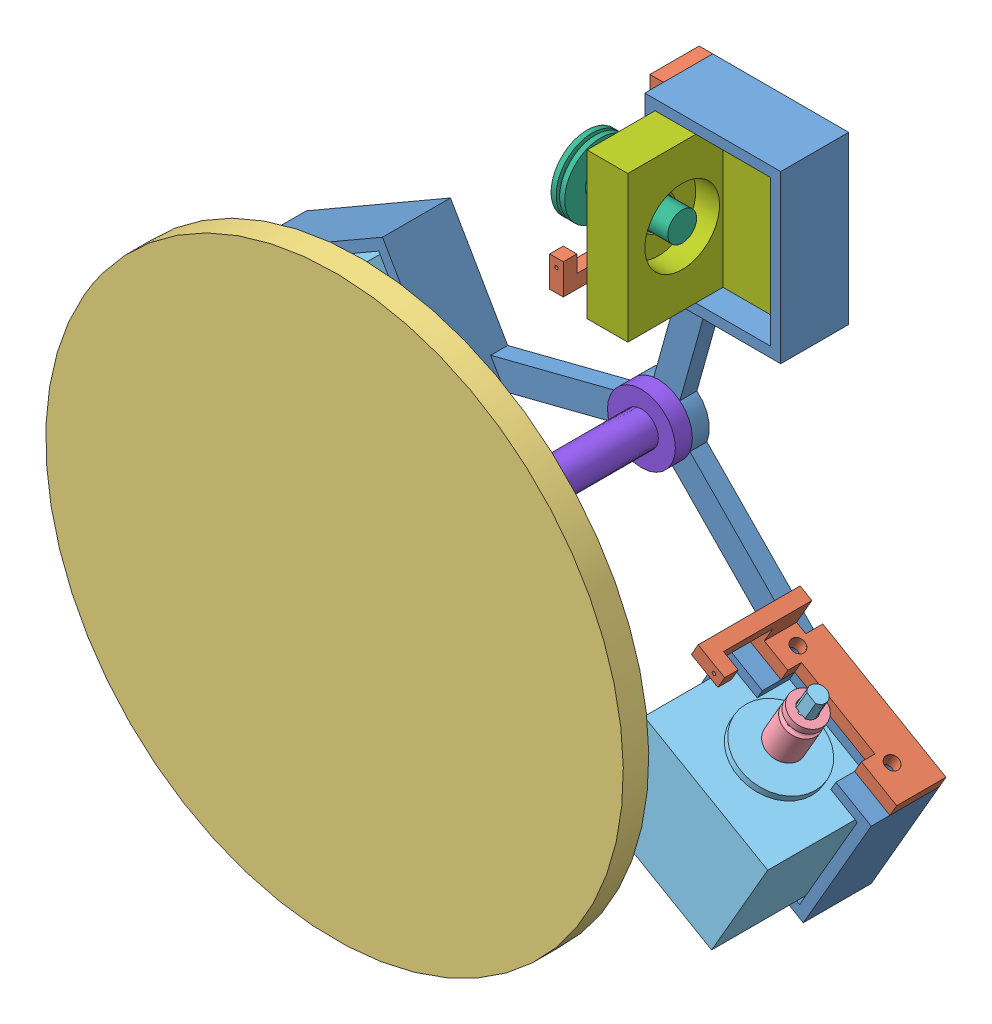
SolidWorks assembly angling2, configuration Default. Lengths in mm.
Overall size (235.3 235.3 100.33).
12 component instances, 8 part files, 31 mates.
Components (placement in the parent):
- Base-1: Base [Default] x (1 0 0) z (0 -1 0) size (186.28 20 188.17)
- cable guide-1: cable guide [Default] at (11 0 0) x (0 -1 0) z (-1 0 0) size (49 35 13)
- panel-1: panel [Default] at (0 0 92.825) x (-0.837169 0.546944 0) z (0 0 1) size (170 170 8.5)
- cable pulley-1: cable pulley [Default] at (-61.8538 -36.866 24) x (-0.866025 -0.5 0) z (-0.5 0.866025 0) size (10 10 14)
- Stepper motor-1: Stepper motor [Default] at (-69.3538 -23.8756 24) x (-0.866025 -0.5 0) z (-0.5 0.866025 0) size (42 42 57)
- Spring pulley-1: Spring pulley [Default] at (26 92.5 -47.5) x (0 -1 0) z (-1 0 0) size (21.17 21.17 28)
- Spring holde-1: Spring holde [Default] at (14 93 3) x (0 -1 0) z (-1 0 0) size (43 37 34)
- Stepper motor-2: Stepper motor [Default] at (53.9878 -48.4904 24) x (0.866025 -0.5 0) z (-0.5 -0.866025 0) size (42 42 57)
- cable pulley-2: cable pulley [Default] at (61.4878 -35.5 24) x (0.866025 -0.5 0) z (-0.5 -0.866025 0) size (10 10 14)
- cable guide-2: cable guide [Default] at (-5.5 -9.5263 0) x (-0.866025 0.5 0) z (0.5 0.866025 0) size (49 35 13)
- cable guide-3: cable guide [Default] at (-5.5 9.5263 0) x (0.866025 0.5 0) z (0.5 -0.866025 0) size (49 35 13)
- Pillar-4: Pillar [Default] x (1 0 0) z (0 -1 0) size (20 97.83 20)
Mates (geometry in assembly coordinates):
- InPlace1: in place: plane of assembly through (11 10.5 -96) normal (-1 0 0); plane of ? through (11 0 0) normal (-1 0 0); moOrthogonalPlaneRef_w of assembly through (11 10.5 -96) normal (-1 0 0); plane of ? through (11 0 0) normal (0 1 0); plane of assembly through (11 10.5 -96) normal (-1 0 0); plane of ? through (11 0 0) normal (0 0 1); plane of ? through (11 96 10.5) normal (-1 0 0); unknown of cable guide-1
- Coincident1: coincident aligned: plane of ?; plane of ?
- Coincident2: coincident aligned: moOrthogonalPlaneRef_w of Base-1; plane of Part3^angling2-1 through (11 0 0) normal (0 0 1)
- Coincident3: coincident anti-aligned: moOrthogonalPlaneRef_w of Base-1; plane of Part3^angling2-1 through (11 0 0) normal (0 -1 0)
- Coincident15: coincident anti-aligned: plane of Base-1 through (14 93 10.5) normal (1 0 0); plane of Part7^angling2-1 through (14 93 3) normal (-1 0 0)
- Coincident17: coincident anti-aligned: plane of Base-1 through (0 0 3) normal (0 0 1); plane of Part7^angling2-1 through (26 93 3) normal (0 0 -1)
- Coincident18: coincident anti-aligned: plane of Base-1 through (48 93 10.5) normal (0 -1 0); plane of Part7^angling2-1 through (26 93 3) normal (0 1 0)
- Coincident19: coincident aligned: plane of Part9^angling2-1 through (19 71.5 24) normal (1 0 0); plane of Part7^angling2-1 through (19 71.5 24) normal (1 0 0)
- Coincident20: coincident anti-aligned: plane of Base-1 through (-104.5404 -4.9308 10.5) normal (0.866025 0.5 0); plane of Part6^angling2-1 through (-104.0404 -5.7968 3) normal (-0.866025 -0.5 0)
- Coincident21: coincident anti-aligned: plane of Base-1 through (0 0 3) normal (0 0 1); plane of Part6^angling2-1 through (-67.6673 15.2032 3) normal (0 0 -1)
- Coincident22: coincident anti-aligned: plane of Base-1 through (-87.5404 -34.3756 10.5) normal (-0.5 0.866025 0); plane of Part6^angling2-1 through (-69.3538 -23.8756 24) normal (0.5 -0.866025 0)
- Coincident24: coincident anti-aligned: plane of cable pulley-1 through (-67.3538 -27.3397 24) normal (-0.5 0.866025 0); plane of Part6^angling2-1 through (-67.3538 -27.3397 24) normal (0.5 -0.866025 0)
- Concentric4: concentric aligned: cylinder of cable pulley-1 through (-60.3538 -39.4641 24) axis (-0.5 0.866025 0) radius 2.7; cylinder of Part6^angling2-1 through (-57.3538 -44.6603 24) axis (-0.5 0.866025 0) radius 2.5
- Parallel1: parallel anti-aligned: plane of cable pulley-1 through (-61.7094 -40.2467 26.2) normal (0 0 -1); plane of Part6^angling2-1 through (-67.3538 -27.3397 26) normal (0 0 1)
- Parallel2: parallel anti-aligned: plane of Part6^angling2-2 through (55.9878 -45.0263 26) normal (0 0 1); plane of cable pulley-2 through (64.3433 -33.6845 26.2) normal (0 0 -1)
- Concentric5: concentric aligned: cylinder of Part6^angling2-2 through (65.9878 -27.7058 24) axis (-0.5 -0.866025 0) radius 2.5; cylinder of cable pulley-2 through (62.9878 -32.9019 24) axis (-0.5 -0.866025 0) radius 2.7
- Coincident26: coincident anti-aligned: plane of Part6^angling2-2 through (55.9878 -45.0263 24) normal (0.5 0.866025 0); plane of cable pulley-2 through (55.9878 -45.0263 24) normal (-0.5 -0.866025 0)
- Coincident27: coincident anti-aligned: plane of Base-1 through (19.3013 -66.5692 10.5) normal (0.5 0.866025 0); plane of Part6^angling2-2 through (37.4878 -77.0692 24) normal (-0.5 -0.866025 0)
- Coincident28: coincident anti-aligned: plane of Base-1 through (36.3013 -37.1244 10.5) normal (0.866025 -0.5 0); plane of Part6^angling2-2 through (19.3013 -66.5692 3) normal (-0.866025 0.5 0)
- Coincident29: coincident anti-aligned: plane of Base-1 through (0 0 3) normal (0 0 1); plane of Part6^angling2-2 through (19.3013 -66.5692 3) normal (0 0 -1)
- Coincident30: coincident anti-aligned: plane of Base-1 through (77.6384 -57.5263 10.5) normal (0.5 0.866025 0); plane of Part3^angling2-2 through (-5.5 -9.5263 0) normal (-0.5 -0.866025 0)
- Concentric6: concentric aligned: cylinder of Base-1 through (136.7567 61.8696 8.5) axis (-0.5 -0.866025 0) radius 2; cylinder of Part3^angling2-2 through (76.7772 -42.0179 8.5) axis (-0.5 -0.866025 0) radius 2
- Concentric7: concentric aligned: cylinder of Base-1 through (109.0439 77.8696 8.5) axis (-0.5 -0.866025 0) radius 2; cylinder of Part3^angling2-2 through (49.0644 -26.0179 8.5) axis (-0.5 -0.866025 0) radius 2
- Parallel3: parallel anti-aligned: plane of panel^angling2-1 through (0 0 92.825) normal (0 0 -1); plane of Part6^angling2-1 through (-67.6673 15.2032 45) normal (0 0 1)
- Concentric10: concentric aligned: cylinder of Part9^angling2-1 through (19 71.5 24) axis (1 0 0) radius 4.25; cylinder of Part7^angling2-1 through (19 71.5 24) axis (1 0 0) radius 11
- Coincident38: coincident anti-aligned: plane of Base-1 through (-88.6384 -38.4737 10.5) normal (0.5 -0.866025 0); plane of Part3^angling2-3 through (-5.5 9.5263 0) normal (-0.5 0.866025 0)
- Concentric11: concentric aligned: cylinder of Base-1 through (-16.4573 -146.4951 8.5) axis (-0.5 0.866025 0) radius 2; cylinder of Part3^angling2-3 through (-74.7772 -45.4821 8.5) axis (-0.5 0.866025 0) radius 2
- Concentric12: concentric aligned: cylinder of Base-1 through (11.2555 -130.4951 8.5) axis (-0.5 0.866025 0) radius 2; cylinder of Part3^angling2-3 through (-47.0644 -29.4821 8.5) axis (-0.5 0.866025 0) radius 2
- Concentric13: concentric anti-aligned: cylinder of Base-1 through (0 0 -4.5) axis (0 0 1) radius 5; cylinder of Part3^angling2-4 through (0 0 5) axis (0 0 -1) radius 5
- Coincident39: coincident anti-aligned: plane of Base-1 through (0 0 5) normal (0 0 1); plane of Part3^angling2-4 through (0 0 5) normal (0 0 -1)
- Concentric14: concentric: sphere of panel^angling2-1; sphere of Part3^angling2-4
